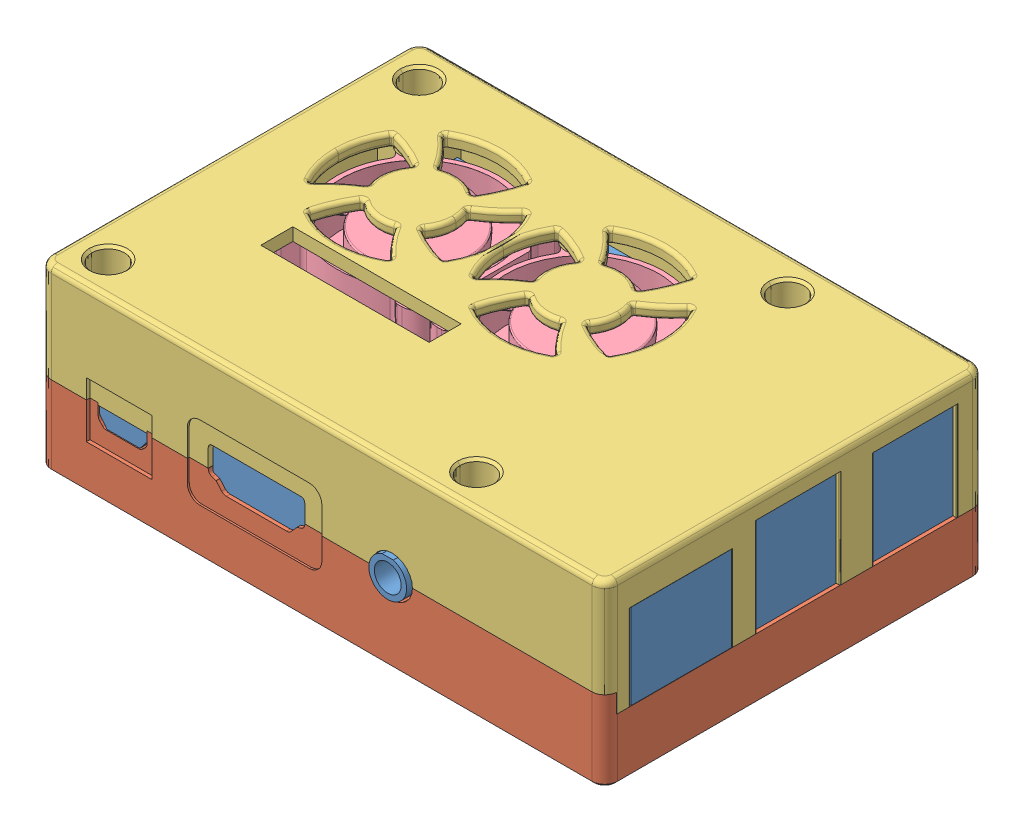
SolidWorks assembly Case Assembly, configuration Default. Lengths in mm.
Overall size (89.48 28.26 60.55).
4 component instances, 4 part files, 12 mates.
Components (placement in the parent):
- Ras Pi 3B+-1: Ras Pi 3B+ [Default] at origin size (89.43 19.13 58.47)
- RPI 3 base-1: RPI 3 base [Default] at (42.5 -0.0254 -28) x (1 0 0) z (0 1 0) size (89.16 59.96 12.65)
- RPI 3 B+ cover-1: RPI 3 B+ cover [Default] at (42.5 -0.0254 -28) x (1 0 0) z (0 1 0) size (89.17 59.96 19.61)
- Dual Fan w HeatSink-1: Dual Fan w HeatSink [Default] at (-119.125 88.4921 53.2463) x (1 0 0) z (0 1 0) size (51.86 25.72 12)
Mates (geometry in assembly coordinates):
- Coincident4: coincident aligned: plane of Ras Pi 3B+-1 through (0 0 0) normal (0 0 1)
- Coincident5: coincident aligned: plane of Ras Pi 3B+-1 through (0 0 0) normal (0 1 0)
- Coincident6: coincident aligned: plane of Ras Pi 3B+-1 through (0 0 0) normal (1 0 0)
- Concentric1: concentric anti-aligned: cylinder of Ras Pi 3B+-1 through (3.5 1.4732 -3.5) axis (0 -1 0) radius 1.375; cylinder of RPI 3 base-1 through (3.5 -29.5754 -3.5) axis (0 1 0) radius 0.9
- Concentric2: concentric anti-aligned: cylinder of Ras Pi 3B+-1 through (3.5 1.4732 -52.5) axis (0 -1 0) radius 1.375; cylinder of RPI 3 base-1 through (3.5 -29.5754 -52.5) axis (0 1 0) radius 0.9
- Coincident7: coincident anti-aligned: plane of Ras Pi 3B+-1 through (82 -0.0254 -3) normal (0 -1 0); plane of RPI 3 base-1 through (42.5 -0.0254 -28) normal (0 1 0)
- Concentric3: concentric anti-aligned: cylinder of Ras Pi 3B+-1 through (3.5 1.4732 -52.5) axis (0 -1 0) radius 1.375; cylinder of RPI 3 B+ cover-1 through (3.5 1.5746 -52.5) axis (0 1 0) radius 1.5
- Concentric4: concentric anti-aligned: cylinder of Ras Pi 3B+-1 through (3.5 1.4732 -3.5) axis (0 -1 0) radius 1.375; cylinder of RPI 3 B+ cover-1 through (3.5 1.5746 -3.5) axis (0 1 0) radius 1.5
- Coincident8: coincident anti-aligned: plane of RPI 3 base-1 through (0 1.5746 -28) normal (0 1 0); plane of RPI 3 B+ cover-1 through (-1.2 1.5746 -10.5) normal (0 -1 0)
- Distance1: distance = 0.5 mm anti-aligned: plane of Ras Pi 3B+-1 through (0 3.9986 0) normal (0 1 0); plane of Dual Fan w HeatSink-1 through (19.25 4.4986 -36.5) normal (0 -1 0)
- Coincident10: coincident aligned: plane of Ras Pi 3B+-1 through (6.5 4.4986 -36) normal (-1 0 0); plane of Dual Fan w HeatSink-1 through (6.5 5.9986 -46.75) normal (-1 0 0)
- Coincident11: coincident aligned: plane of Ras Pi 3B+-1 through (17 4.4986 -49.25) normal (0 0 -1); plane of Dual Fan w HeatSink-1 through (14 5.9986 -49.25) normal (0 0 -1)
